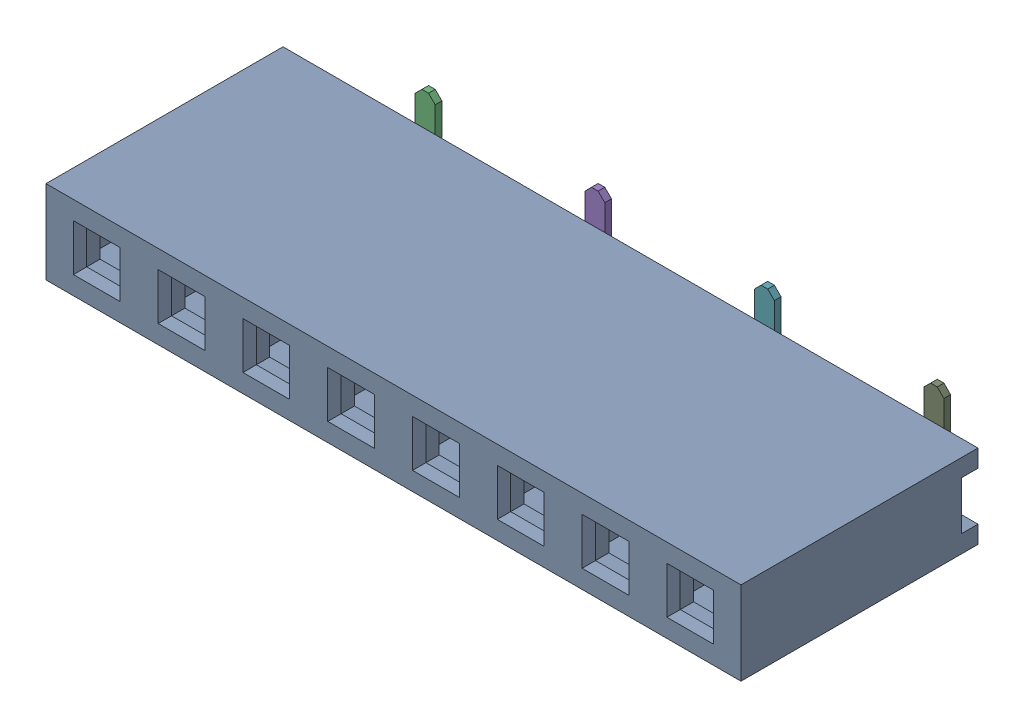
SolidWorks assembly J1, configuration Default. Lengths in mm.
Overall size (20.82 4.05 7.5).
10 component instances, 2 part files, 0 mates.
Components (placement in the parent):
- 61000813321-1: 61000813321 [Default] at (23.4999 29.2999 3.95) x (1 0 0) z (0 0 1) size (20.82 4.05 7.5)
  - 6100081xx21-1: 6100081xx21 [Default] at origin size (20.82 2.5 7.1)
  - 6100xx1xx21_PIN-1: 6100xx1xx21_PIN [Default] at (-8.89 -0.725 -3.04) x (-1 0 0) z (0 0 -1) size (2 2.81 6.11)
  - 6100xx1xx21_PIN-2: 6100xx1xx21_PIN [Default] at (-6.35 0.725 -3.04) x (1 0 0) z (0 0 -1) size (2 2.81 6.11)
  - 6100xx1xx21_PIN-3: 6100xx1xx21_PIN [Default] at (-3.81 -0.725 -3.04) x (-1 0 0) z (0 0 -1) size (2 2.81 6.11)
  - 6100xx1xx21_PIN-4: 6100xx1xx21_PIN [Default] at (-1.27 0.725 -3.04) x (1 0 0) z (0 0 -1) size (2 2.81 6.11)
  - 6100xx1xx21_PIN-5: 6100xx1xx21_PIN [Default] at (1.27 -0.725 -3.04) x (-1 0 0) z (0 0 -1) size (2 2.81 6.11)
  - 6100xx1xx21_PIN-6: 6100xx1xx21_PIN [Default] at (3.81 0.725 -3.04) x (1 0 0) z (0 0 -1) size (2 2.81 6.11)
  - 6100xx1xx21_PIN-7: 6100xx1xx21_PIN [Default] at (6.35 -0.725 -3.04) x (-1 0 0) z (0 0 -1) size (2 2.81 6.11)
  - 6100xx1xx21_PIN-8: 6100xx1xx21_PIN [Default] at (8.89 0.725 -3.04) x (1 0 0) z (0 0 -1) size (2 2.81 6.11)
